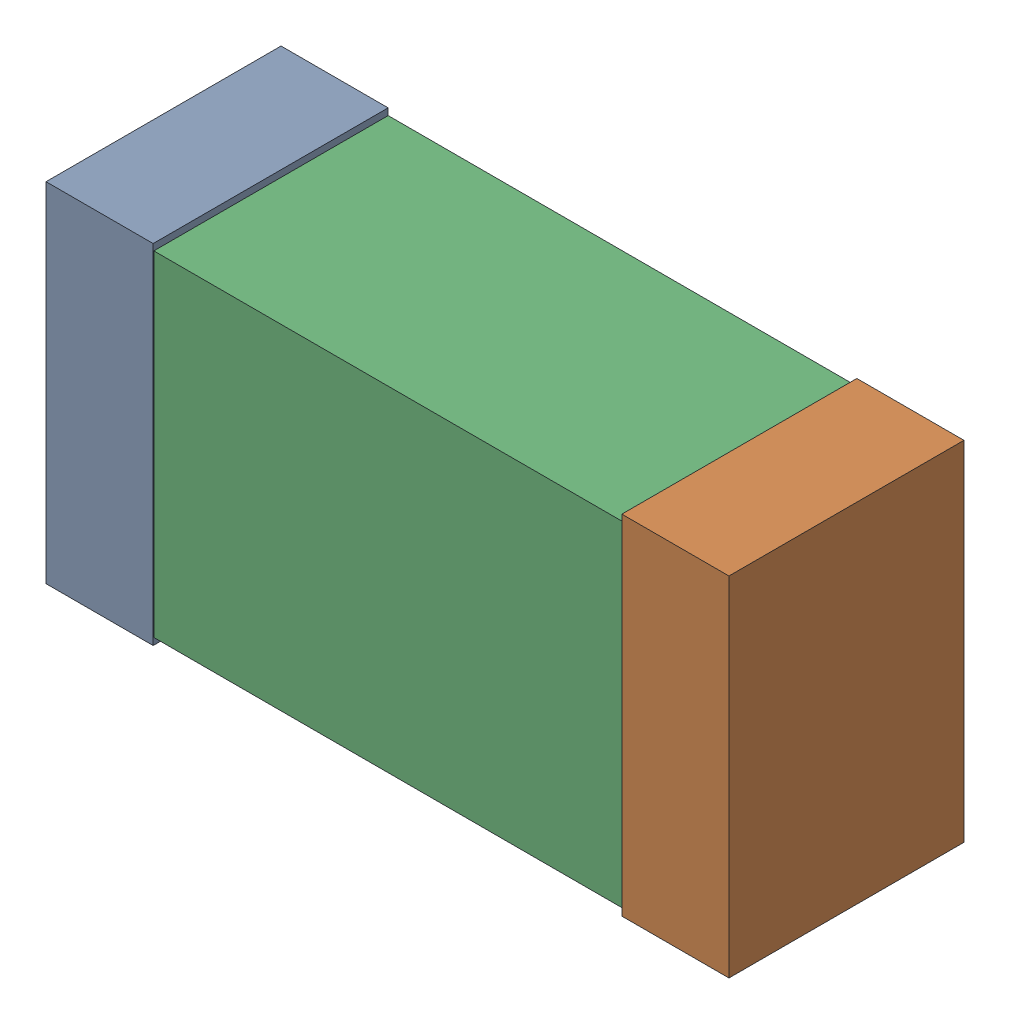
SolidWorks assembly C48, configuration Default. Lengths in mm.
Overall size (1.02 0.52 0.35).
6 component instances, 2 part files, 0 mates.
Components (placement in the parent):
- 870940480-1: 870940480 [Default] at (84.533 22.733 0) size (0.16 0.52 0.35)
  - Extruded-1: Extruded [Default] at origin size (0.16 0.52 0.35)
- 870940480-2: 870940480 [Default] at (85.393 22.733 0) size (0.16 0.52 0.35)
  - Extruded-1: Extruded [Default] at origin size (0.16 0.52 0.35)
- 870940640-1: 870940640 [Default] at (84.963 22.733 0) size (1 0.5 0.35)
  - Extruded_2-1: Extruded_2 [Default] at origin size (1 0.5 0.35)
